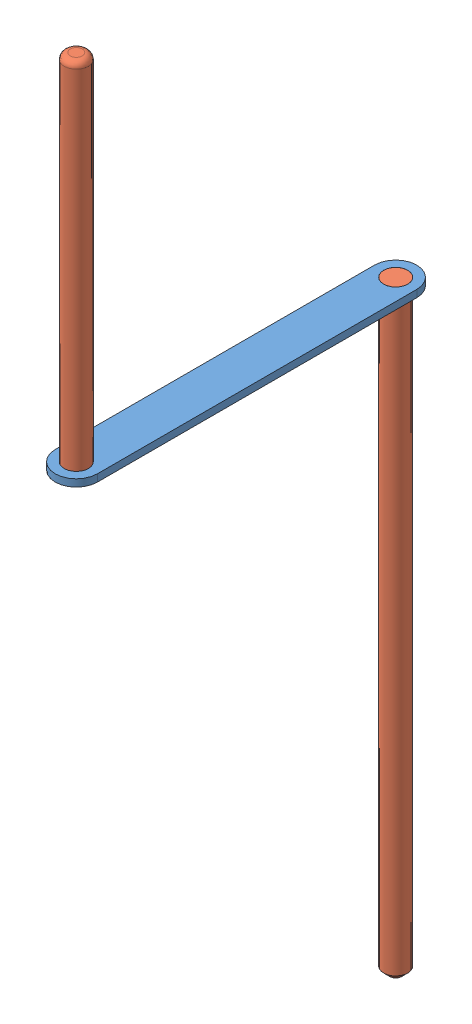
SolidWorks assembly Assem1, configuration Default. Lengths in mm.
Overall size (35 794 300).
3 component instances, 2 part files, 4 mates.
Components (placement in the parent):
- handle-link-1: handle-link [Default] at origin size (35 6 300)
- bar-1: bar [300mm] at (0 0 132.5) x (0.999562 0 -0.029607) z (0 1 0) size (20 20 300)
- bar-2: bar [Chamfered] at (0 -494 -132.5) x (-0.665343 0 0.746538) z (0 1 0) size (20 20 500)
Mates (geometry in assembly coordinates):
- Concentric1: concentric aligned: cylinder of handle-link-1 through (0 6 132.5) axis (0 -1 0) radius 10; cylinder of bar-1 through (0 300 132.5) axis (0 -1 0) radius 10
- Coincident1: coincident aligned: plane of handle-link-1 through (0 0 0) normal (0 -1 0); plane of bar-1 through (0 0 132.5) normal (0 -1 0)
- Concentric2: concentric: cylinder of handle-link-1 through (0 6 -132.5) axis (0 -1 0) radius 10; cylinder of bar-2 through (0 38.7378 -132.5) axis (0 -1 0) radius 10
- Coincident2: coincident aligned: plane of handle-link-1 through (0 6 0) normal (0 1 0); plane of bar-2 through (0 6 -132.5) normal (0 1 0)
